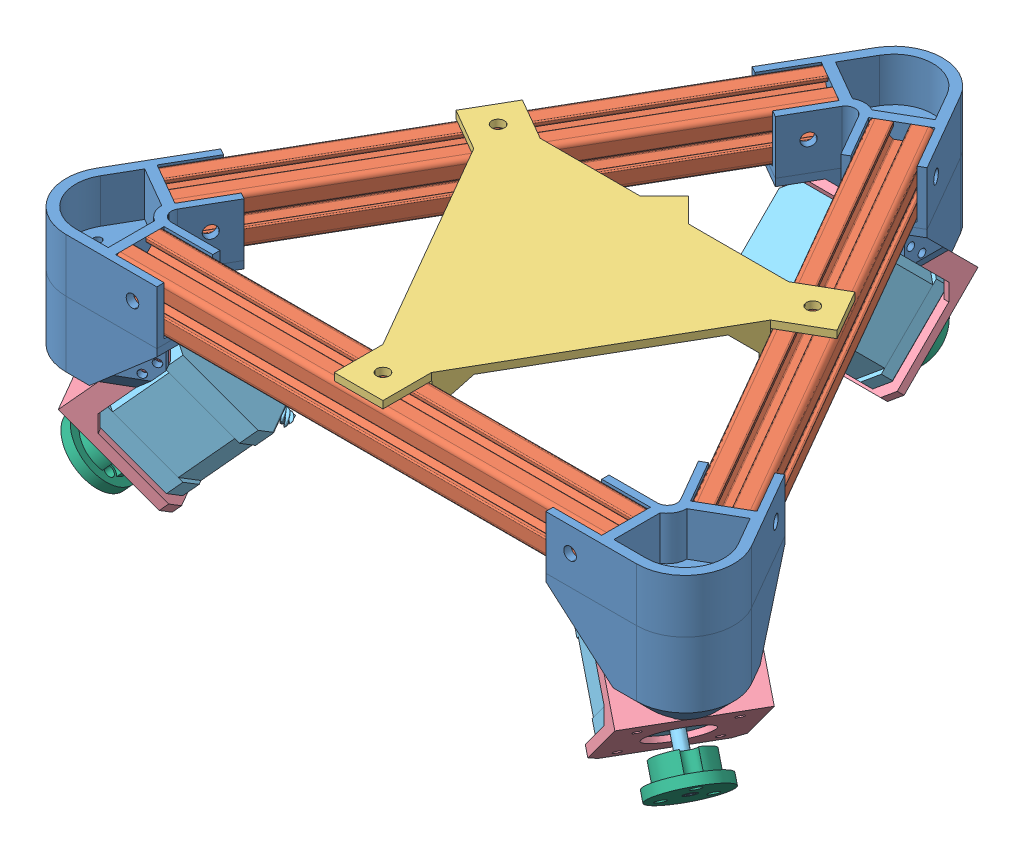
SolidWorks assembly Robot Assembly, configuration Standard. Lengths in mm.
Overall size (305.26 109.87 269.08).
19 component instances, 6 part files, 32 mates.
Components (placement in the parent):
- Extrusion_Corner-1: Extrusion_Corner [Standard] at origin size (71.96 57 55.32)
- Alu_Extrusion-1: Alu_Extrusion [Standard] at (-14.7224 12 25.5) x (-0.866025 0 -0.5) z (-0.5 0 0.866025) size (20 20 200)
- Alu_Extrusion-2: Alu_Extrusion [Standard] at (14.7224 12 25.5) x (0.866025 0 -0.5) z (0.5 0 0.866025) size (20 20 200)
- Extrusion_Corner-2: Extrusion_Corner [Standard] at (-129.4449 0 224.2051) x (-0.5 0 -0.866025) z (0.866025 0 -0.5) size (71.96 57 55.32)
- Extrusion_Corner-3: Extrusion_Corner [Standard] at (129.4449 0 224.2051) x (-0.5 0 0.866025) z (-0.866025 0 -0.5) size (71.96 57 55.32)
- Alu_Extrusion-3: Alu_Extrusion [Standard] at (-100 12 224.2051) x (0 0 -1) z (1 0 0) size (20 20 200)
- Main_Plate-1: Main_Plate [Standard] at (-0.0046 22 149.4674) size (156.77 23 135.77)
- Stepper_Assembly-1: Stepper_Assembly [Standard] at (-64.8316 -24.1656 22.8034) x (-1 0 0) z (0 0.707107 0.707107) size (48 53.25 62)
  - Stepper_holder-1: Stepper_holder [Standard] at (-64.8316 -5.4083 0) size (48 49 44)
  - nema17-1: nema17 [По умолчанию] at (-85.8316 40.5917 21) x (0 -1 0) z (1 0 0) size (47.25 61 42)
  - Wheel_Hub-1: Wheel_Hub [Standard] at (-64.8316 19.5917 -40) size (28 28 12)
- Stepper_Assembly-2: Stepper_Assembly [Standard] at (142.1123 -24.1656 156.6575) x (0.5 0 -0.866025) z (-0.612372 0.707107 -0.353553) size (48 53.25 62)
  - Stepper_holder-1: Stepper_holder [Standard] at (-64.8316 -5.4083 0) size (48 49 44)
  - nema17-1: nema17 [По умолчанию] at (-85.8316 40.5917 21) x (0 -1 0) z (1 0 0) size (47.25 61 42)
  - Wheel_Hub-1: Wheel_Hub [Standard] at (-64.8316 19.5917 -40) size (28 28 12)
- Stepper_Assembly-3: Stepper_Assembly [Standard] at (-77.2807 -24.1656 268.9492) x (0.5 0 0.866025) z (0.612372 0.707107 -0.353553) size (48 53.25 62)
  - Stepper_holder-1: Stepper_holder [Standard] at (-64.8316 -5.4083 0) size (48 49 44)
  - nema17-1: nema17 [По умолчанию] at (-85.8316 40.5917 21) x (0 -1 0) z (1 0 0) size (47.25 61 42)
  - Wheel_Hub-1: Wheel_Hub [Standard] at (-64.8316 19.5917 -40) size (28 28 12)
Mates (geometry in assembly coordinates):
- Deckungsgleich1: coincident aligned: plane of Alu_Extrusion-1 through (-112.5574 2 199.9551) normal (0 -1 0); plane of Alu_Extrusion-3 through (100 2 221.7051) normal (0 -1 0)
- Deckungsgleich2: coincident aligned: plane of Alu_Extrusion-1 through (-112.5574 2 199.9551) normal (0 -1 0); plane of Alu_Extrusion-2 through (106.0622 2 203.7051) normal (0 -1 0)
- Deckungsgleich3: coincident anti-aligned: plane of Alu_Extrusion-1 through (-112.5574 2 199.9551) normal (0 -1 0); plane of Extrusion_Corner-2 through (-100 2 207.2051) normal (0 1 0)
- Deckungsgleich4: coincident anti-aligned: plane of Alu_Extrusion-1 through (-112.5574 2 199.9551) normal (0 -1 0); plane of Extrusion_Corner-2 through (-100 2 207.2051) normal (0 1 0)
- Deckungsgleich5: coincident anti-aligned: plane of Alu_Extrusion-1 through (-112.5574 2 199.9551) normal (0 -1 0); plane of Extrusion_Corner-3 through (100 2 207.2051) normal (0 1 0)
- Deckungsgleich6: coincident anti-aligned: plane of Alu_Extrusion-1 through (-112.5574 2 199.9551) normal (0 -1 0); plane of Extrusion_Corner-3 through (100 2 207.2051) normal (0 1 0)
- Deckungsgleich7: coincident anti-aligned: plane of Alu_Extrusion-1 through (-112.5574 2 199.9551) normal (0 -1 0); plane of Extrusion_Corner-1 through (0 2 34) normal (0 1 0)
- Deckungsgleich8: coincident anti-aligned: plane of Alu_Extrusion-1 through (-112.5574 2 199.9551) normal (0 -1 0); plane of Extrusion_Corner-1 through (0 2 34) normal (0 1 0)
- Deckungsgleich9: coincident anti-aligned: plane of Extrusion_Corner-3 through (100 22 224.2051) normal (-1 0 0); plane of Alu_Extrusion-3 through (100 12 224.2051) normal (1 0 0)
- Deckungsgleich10: coincident anti-aligned: plane of Alu_Extrusion-2 through (114.7224 12 198.7051) normal (0.5 0 0.866025); plane of Extrusion_Corner-3 through (114.7224 22 198.7051) normal (-0.5 0 -0.866025)
- Deckungsgleich11: coincident anti-aligned: plane of Extrusion_Corner-1 through (14.7224 22 25.5) normal (0.5 0 0.866025); plane of Alu_Extrusion-2 through (14.7224 12 25.5) normal (-0.5 0 -0.866025)
- Deckungsgleich12: coincident anti-aligned: plane of Alu_Extrusion-1 through (-114.7224 12 198.7051) normal (-0.5 0 0.866025); plane of Extrusion_Corner-2 through (-114.7224 22 198.7051) normal (0.5 0 -0.866025)
- Deckungsgleich13: coincident anti-aligned: plane of Extrusion_Corner-1 through (-14.7224 22 25.5) normal (-0.5 0 0.866025); plane of Alu_Extrusion-1 through (-14.7224 12 25.5) normal (0.5 0 -0.866025)
- Deckungsgleich14: coincident anti-aligned: plane of Extrusion_Corner-2 through (-100 22 224.2051) normal (1 0 0); plane of Alu_Extrusion-3 through (-100 12 224.2051) normal (-1 0 0)
- Deckungsgleich15: coincident anti-aligned: plane of Alu_Extrusion-1 through (-123.3827 22 193.7051) normal (-0.866025 0 -0.5); plane of Extrusion_Corner-2 through (-138.1051 22 219.2051) normal (0.866025 0 0.5)
- Deckungsgleich16: coincident anti-aligned: plane of Extrusion_Corner-2 through (-129.4449 22 234.2051) normal (0 0 -1); plane of Alu_Extrusion-3 through (100 22 234.2051) normal (0 0 1)
- Deckungsgleich17: coincident anti-aligned: plane of Extrusion_Corner-1 through (-8.6603 22 -5) normal (0.866025 0 0.5); plane of Alu_Extrusion-1 through (-123.3827 22 193.7051) normal (-0.866025 0 -0.5)
- Deckungsgleich18: coincident anti-aligned: plane of Alu_Extrusion-2 through (123.3827 14.5 193.7051) normal (0.866025 0 -0.5); plane of Extrusion_Corner-3 through (138.1051 22 219.2051) normal (-0.866025 0 0.5)
- Deckungsgleich19: coincident aligned: plane of Alu_Extrusion-3 through (100 9.5 231.2051) normal (0 0 1); plane of ? through (10 207.0898 231.2051) normal (0 0 1)
- Deckungsgleich20: coincident aligned: plane of Alu_Extrusion-2 through (122.5167 2 192.2051) normal (0.866025 0 -0.5); plane of ? through (67.5167 207.0898 96.9423) normal (0.866025 0 -0.5)
- Deckungsgleich22: coincident aligned: plane of Alu_Extrusion-3 through (100 22 234.2051) normal (0 0 1); plane of Main_Plate-1 through (-10.0046 25 234.2051) normal (0 0 1)
- Deckungsgleich23: coincident aligned: plane of Alu_Extrusion-2 through (123.3827 14.5 193.7051) normal (0.866025 0 -0.5); plane of Main_Plate-1 through (68.3804 25 98.4383) normal (0.866025 0 -0.5)
- Deckungsgleich24: coincident anti-aligned: plane of Alu_Extrusion-3 through (100 22 226.7051) normal (0 1 0); plane of Main_Plate-1 through (-0.0046 22 149.4674) normal (0 -1 0)
- Abstand1: distance = 0.05 mm anti-aligned: plane of Stepper_Assembly-1/Stepper_holder-1 through (24 -38.019 5.5442) normal (1 0 0); plane of Extrusion_Corner-1 through (24.05 -13.9774 36.6569) normal (-1 0 0)
- Deckungsgleich27: coincident anti-aligned: plane of Extrusion_Corner-1 through (0 -35 4.3205) normal (0 -0.707107 0.707107); plane of Stepper_Assembly-1/Stepper_holder-1 through (0 -20.3413 18.9792) normal (0 0.707107 -0.707107)
- Deckungsgleich28: coincident aligned: plane of Extrusion_Corner-1 through (27.05 -13.9774 36.6569) normal (0 0 1); plane of Stepper_Assembly-1/Stepper_holder-1 through (0 -13.9774 36.6569) normal (0 0 1)
- Deckungsgleich29: coincident anti-aligned: plane of Extrusion_Corner-3 through (125.7032 -35 222.0448) normal (-0.612372 -0.707107 -0.353553); plane of Stepper_Assembly-2/Stepper_holder-1 through (113.0084 -20.3413 214.7155) normal (0.612372 0.707107 0.353553)
- Abstand2: distance = 0.05 mm anti-aligned: plane of Stepper_Assembly-2/Stepper_holder-1 through (136.6435 -38.019 200.6484) normal (0.5 0 -0.866025); plane of Extrusion_Corner-3 through (109.7241 -13.9774 185.0487) normal (-0.5 0 0.866025)
- Deckungsgleich31: coincident aligned: plane of Extrusion_Corner-3 through (84.1741 -13.9774 229.3026) normal (-0.866025 0 -0.5); plane of Stepper_Assembly-2/Stepper_holder-1 through (97.6991 -13.9774 205.8767) normal (-0.866025 0 -0.5)
- Deckungsgleich32: coincident anti-aligned: plane of Extrusion_Corner-2 through (-125.7032 -35 222.0448) normal (0.612372 -0.707107 -0.353553); plane of Stepper_Assembly-3/Stepper_holder-1 through (-113.0084 -20.3413 214.7155) normal (-0.612372 0.707107 0.353553)
- Abstand3: distance = 0.05 mm anti-aligned: plane of Stepper_Assembly-3/Stepper_holder-1 through (-112.6435 -38.019 242.2176) normal (0.5 0 0.866025); plane of Extrusion_Corner-2 through (-85.6741 -13.9774 226.7046) normal (-0.5 0 -0.866025)
- Deckungsgleich34: coincident aligned: plane of Extrusion_Corner-2 through (-111.2241 -13.9774 182.4507) normal (0.866025 0 -0.5); plane of Stepper_Assembly-3/Stepper_holder-1 through (-97.6991 -13.9774 205.8767) normal (0.866025 0 -0.5)
